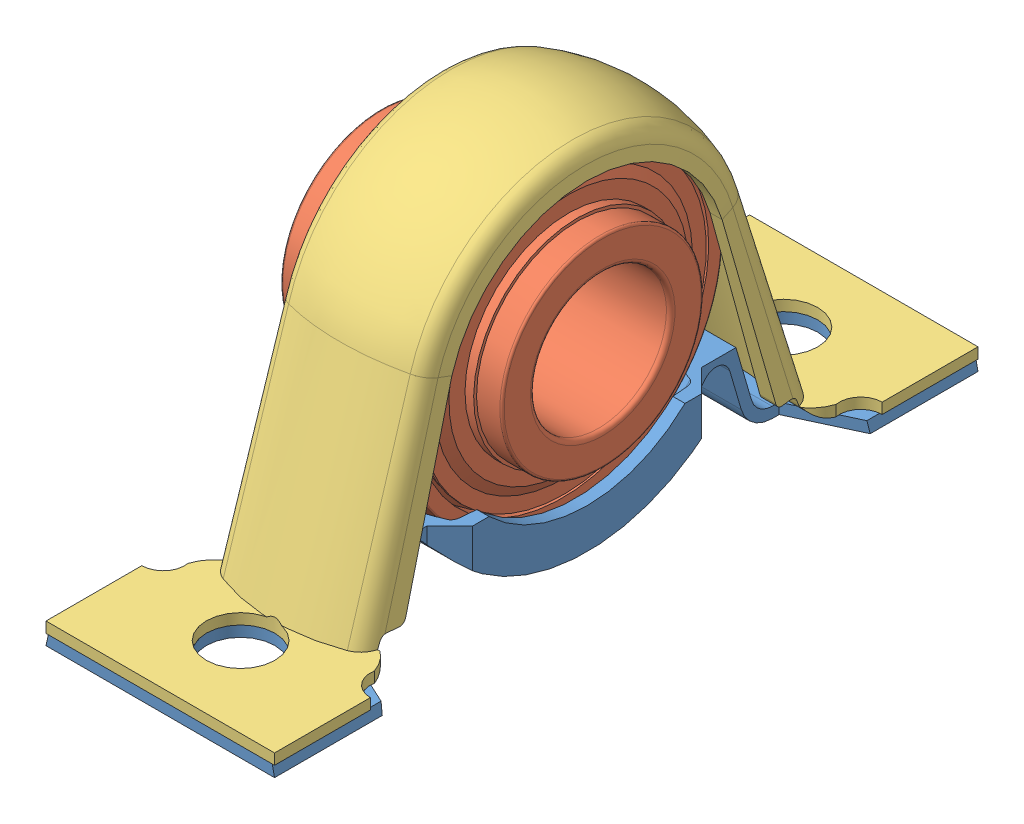
SolidWorks assembly Chumacera3_4, configuration Predeterminado. Lengths in mm.
Overall size (34.3 65.52 98.5).
3 component instances, 3 part files, 2 mates.
Components (placement in the parent):
- housingP 47-housing-1: housingP 47-housing [Predeterminado] x (0 0 1) z (-1 0 0) size (98.5 11.15 32)
- YAR 204-012-2RF-28_2103003912-bearing-1: YAR 204-012-2RF-28_2103003912-bearing [Predeterminado] x (-1 0 0) z (0 0.815803 0.57833) size (31 47 47)
- housing2P 47-housing_arc-1: housing2P 47-housing_arc [Predeterminado] x (0 0 -1) z (1 0 0) size (98.5 49 32)
Mates (geometry in assembly coordinates):
- Concéntrica1: concentric: sphere of housingP 47-housing-1; sphere of YAR 204-012-2RF-28_2103003912-bearing-1
- Paralelo1: parallel aligned: plane of housingP 47-housing-1 through (-10.5 -19.7097 0) normal (-1 0 0); plane of YAR 204-012-2RF-28_2103003912-bearing-1 through (-18.3 -5.8556 8.26) normal (-1 0 0)
